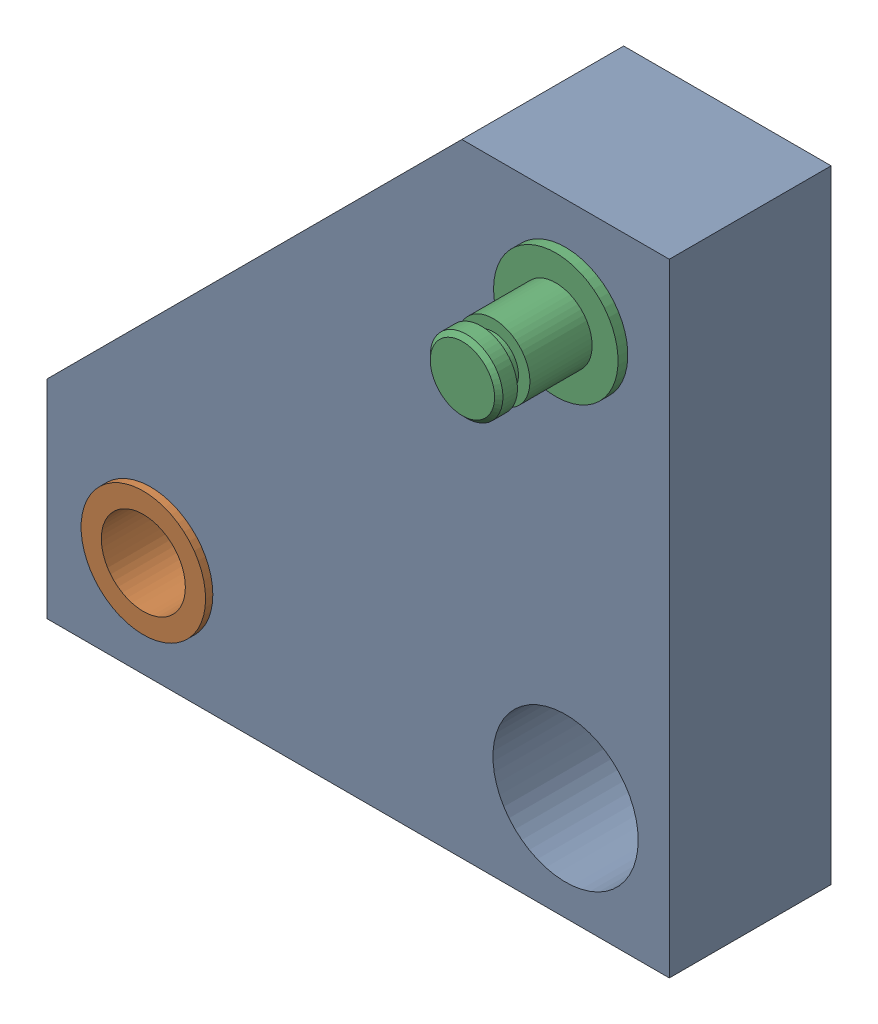
SolidWorks assembly Palonnier avec axe circlips, configuration Défaut. Lengths in mm.
Overall size (30 30 13.12).
3 component instances, 3 part files, 4 mates.
Components (placement in the parent):
- Palonnier-1: Palonnier [Défaut] at (9.4027 -14.2489 0) size (30 30 7.8)
- Bague Inox-1: Bague Inox [Défaut] at (-15.5973 -9.2489 0) size (6 6 8.5)
- Axe pour circlips-1: Axe pour circlips [Défaut] at (4.4027 10.7511 8.87) x (0 0 1) z (-1 0 0) size (10.5 6 6)
Mates (geometry in assembly coordinates):
- Coaxiale1: concentric aligned: cylinder of Palonnier-1 through (-15.5973 -9.2489 3.9) axis (0 0 -1) radius 2.99; cylinder of Bague Inox-1 through (-15.5973 -9.2489 4.25) axis (0 0 -1) radius 3
- Coaxiale2: concentric aligned: cylinder of Palonnier-1 through (4.4027 10.7511 3.9) axis (0 0 -1) radius 2.99; cylinder of Axe pour circlips-1 through (4.4027 10.7511 8.87) axis (0 0 -1) radius 3
- Distance2: distance = 4.97 mm aligned: plane of Palonnier-1; plane of Axe pour circlips-1 through (4.4027 10.7511 8.87) normal (0 0 1)
- Coïncidente3: coincident aligned: plane of Palonnier-1; plane of Bague Inox-1
